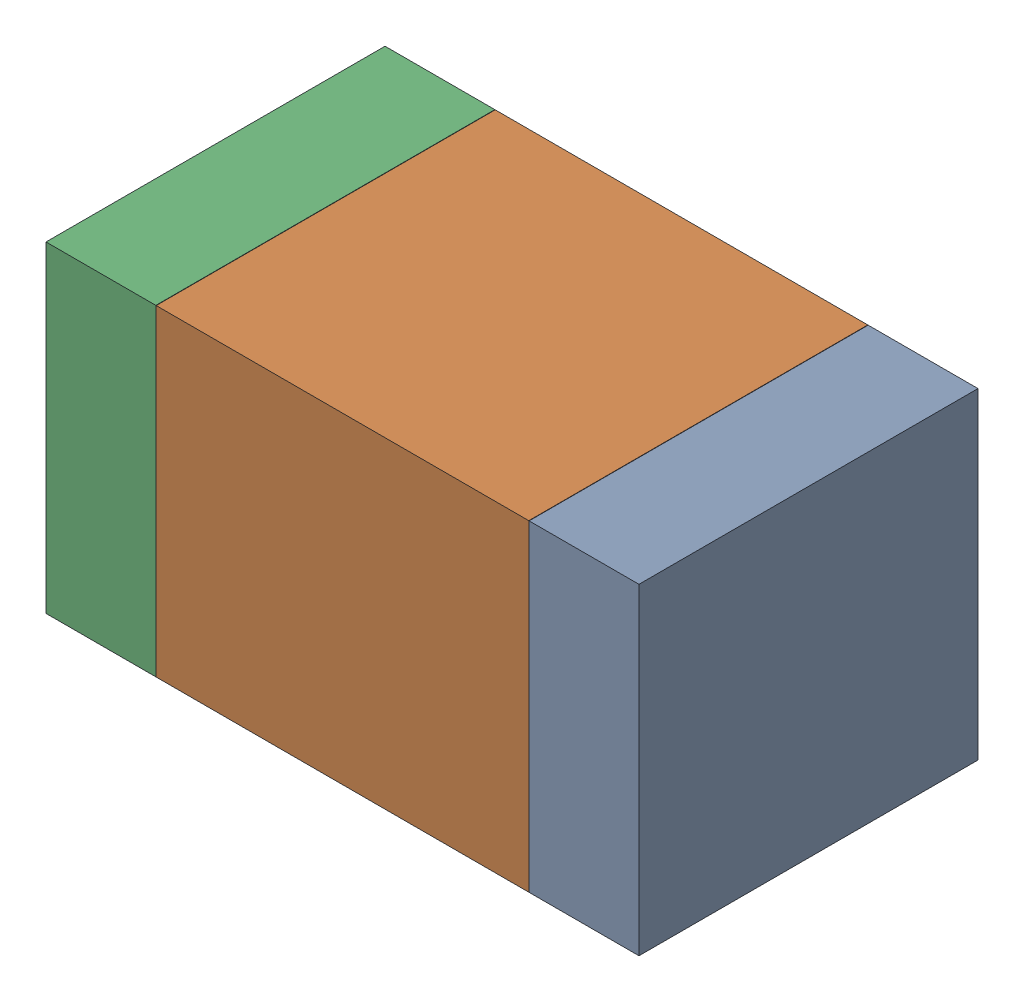
SolidWorks assembly R23, configuration Default. Lengths in mm.
Overall size (1.75 0.95 1).
6 component instances, 2 part files, 0 mates.
Components (placement in the parent):
- 6575498272-1: 6575498272 [Default] at (16.7145 21.082 0) size (0.32 0.95 1)
  - Extruded_8-1: Extruded_8 [Default] at origin size (0.32 0.95 1)
- 6575498112-1: 6575498112 [Default] at (16.002 21.082 0) size (1.1 0.95 1)
  - Extruded_9-1: Extruded_9 [Default] at origin size (1.1 0.95 1)
- 6575498272-2: 6575498272 [Default] at (15.2895 21.082 0) size (0.32 0.95 1)
  - Extruded_8-1: Extruded_8 [Default] at origin size (0.32 0.95 1)
